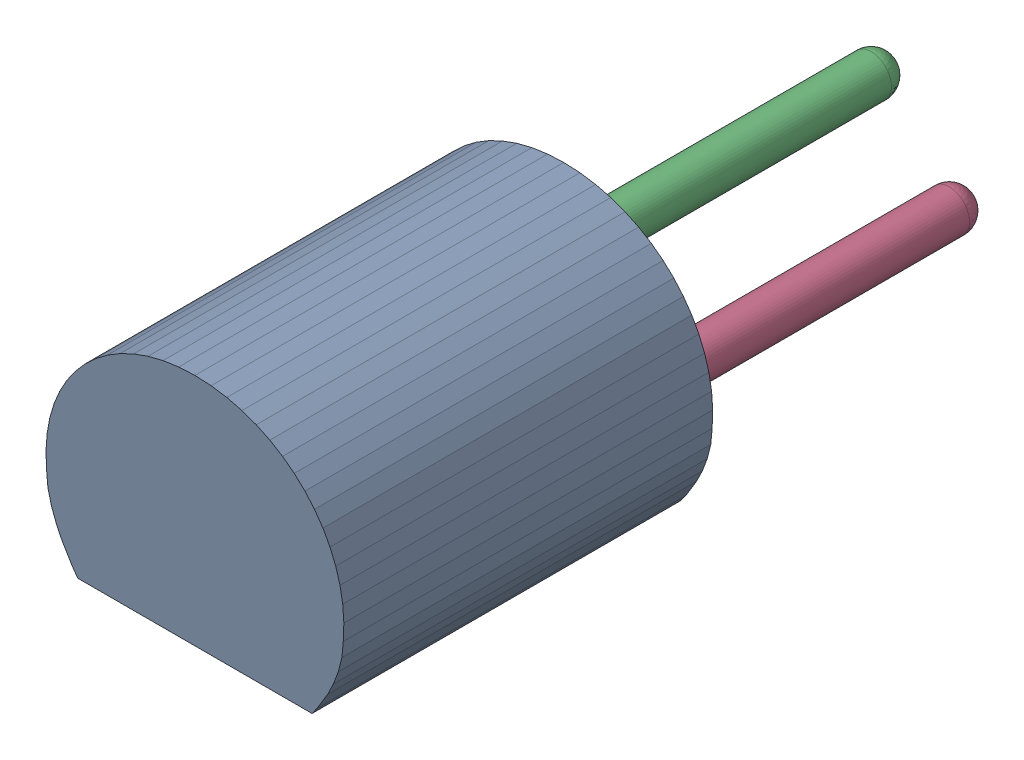
SolidWorks assembly Open CASCADE STEP translator 6.8 1.25.1, configuration Défaut. Lengths in mm.
Overall size (4.85 3.81 11.33).
4 component instances, 4 part files, 0 mates.
Components (placement in the parent):
- Body_1_12-1: Body_1_12 [Défaut] at origin size (4.85 3.81 6)
- Pin_1_9-1: Pin_1_9 [Défaut] at (-1.27 -1.27 0) x (0 -1 0) z (0 0 1) size (0.66 0.66 8.66)
- Pin_2_9-1: Pin_2_9 [Défaut] at (-1.27 1.27 0) x (0 -1 0) z (0 0 1) size (0.66 0.66 8.66)
- Pin_3_5-1: Pin_3_5 [Défaut] at (1.27 1.27 0) x (0 -1 0) z (0 0 1) size (0.66 0.66 8.66)
